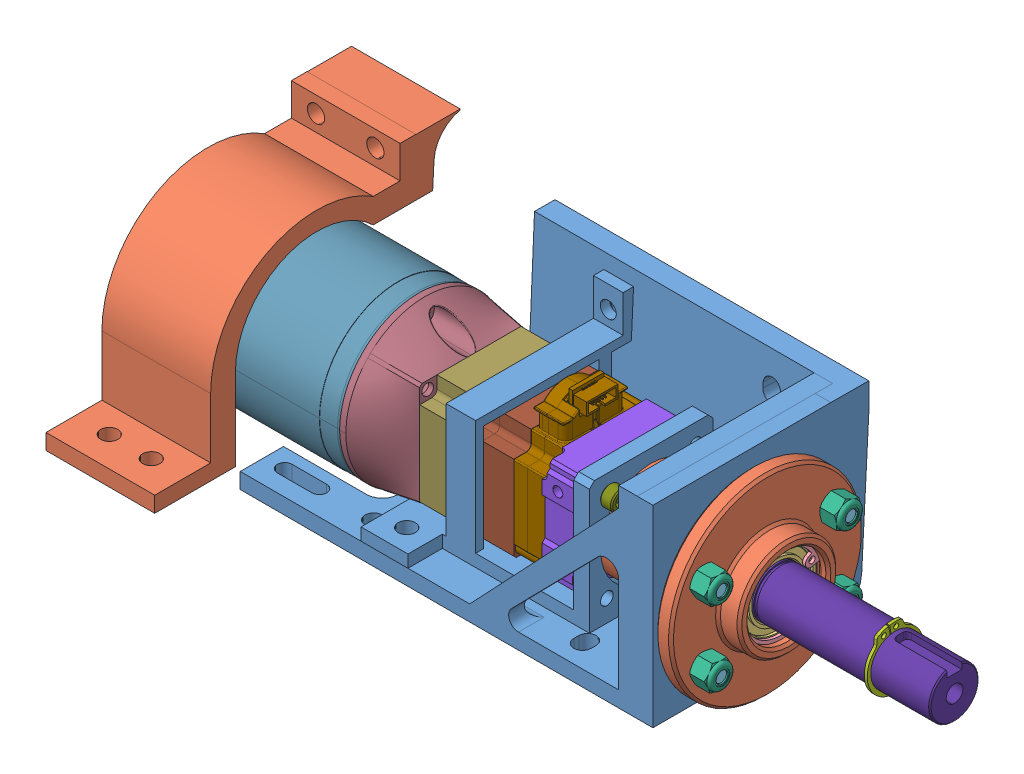
SolidWorks assembly assemblage moteur et sol - V2, configuration Default. Lengths in mm.
Overall size (344.65 86 163.91).
36 component instances, 20 part files, 9 mates.
Components (placement in the parent):
- braquette_bleue_46.2_SLDPRT-1: braquette_bleue_46.2_SLDPRT [Default] at (145.2849 88.8778 231.2871) x (-1 0 0) z (0 0 -1) size (205.75 78 138.28)
- A12220103_FRONT_BRACKET_ASSEMBLY-1: A12220103_FRONT_BRACKET_ASSEMBLY [Default] at (109.7849 121.8778 191.2871) x (0 1 0) z (1 0 0) size (78 78 534.65)
  - A12220101_FRONT_CASE_ASSEMBLY-1: A12220101_FRONT_CASE_ASSEMBLY [Default] at origin size (78 78 141.2)
    - 12220103_FRONT_HOUSING-1: 12220103_FRONT_HOUSING [Default] at (-52 141.0744 -192.9876) x (0 0 -1) z (1 0 0) size (60 78 78)
    - BALL BEARING-1: BALL BEARING [6656K203] at origin size (32 32 10)
    - BALL BEARING-2: BALL BEARING [6656K203] at (0 0 41) size (32 32 10)
    - Internal Retaining Ring (98455A129)-1: Internal Retaining Ring (98455A129) [98455A129] at (0.0361 0.7992 46) x (0.998982 -0.045107 0) z (0 0 1) size (34.4 33.81 1.2)
  - M6 x 20mm Steel Hex Head Screw (91310A333)-2: M6 x 20mm Steel Hex Head Screw (91310A333) [91310A333] at (-15.125 -26.1973 37.15) x (0 0 1) z (-0.44141 0.897306 0) size (24.4 11.55 10)
  - M6 x 1mm Steel Hex LockNut (90592A016)-1: M6 x 1mm Steel Hex LockNut (90592A016) [97260A101] at (15.125 -26.1973 41.85) x (0.928554 -0.371196 0) z (-0.371196 -0.928554 0) size (10 8.38 11.55)
  - 20MM External Retaining Ring (98541A123)-4: 20MM External Retaining Ring (98541A123) [98541A123] at (0 0 92.94) x (0 0 1) z (-0.186581 0.98244 0) size (1.2 25.1 22.76)
  - A12220110_FRONT_SHAFT_ASSEMBLY-1: A12220110_FRONT_SHAFT_ASSEMBLY [Default] at (1.7896 0 -19.01) x (0 -1 0) z (0 0 1) size (64.01 67.32 307.03)
    - A12220105_MOTOR_BRACKET_ASSEMBLY-1: A12220105_MOTOR_BRACKET_ASSEMBLY [Default] at origin size (64.01 67.32 280.24) (flexible)
      - 12220106-051 MiniCIM Motor Assembly-1: 12220106-051 MiniCIM Motor Assembly [Default] at origin size (64.01 67.32 218.97)
        - Gearbox Assembly-1: Gearbox Assembly [Default] at (34.0244 -12.4567 -92.7758) x (0 0 1) z (-1 0 0) size (123.35 56.32 44.45)
          - Output Housing-2: Output Housing [Default] at (64.8023 -0.856 18.2213) x (1 0 0) z (0 -1 0) size (75.7 44.45 56.32)
            - Housing-1: Housing [Default] at (19.8785 -6.4219 -11.5232) size (18.13 44.45 42)
            - Encoder.step-1: Encoder.step [Default] at (12.6785 15.8031 -11.5232) x (0 0 1) z (-1 0 0) size (56.32 42 21.21)
            - Gearbox_output_shaft-1: Gearbox_output_shaft [Default] at origin size (63.51 17 17)
          - Ring Gears-1: Ring Gears [Default] at (71.9808 10.6671 11.7994) x (1 0 0) z (0 -1 0) size (32.2 42 42)
          - Ring Gear Stage 3-1: Ring Gear Stage 3 [Default] at (59.2808 10.6671 11.7994) x (1 0 0) z (0 -1 0) size (28.65 42 42)
        - CIM Adaptor.step-1: CIM Adaptor.step [Default] at (0 -1.7896 -68.72) x (0 -1 0) z (-1 0 0) size (64.01 21.63 64.01)
        - Mini CIM-1: Mini CIM [Default] at (0 -1.7896 -80.245) x (0 0 -1) z (1 0 0) size (101.22 64.01 64.01)
        - 8-32 X 3IN LG - Black-Oxide Alloy Steel Socket Head Screw (90044A516)-1: 8-32 X 3IN LG - Black-Oxide Alloy Steel Socket Head Screw (90044A516) [90044A516] at (17.5 15.7104 -75.245) x (-0.08536 0.99635 0) z (0 0 -1) size (6.86 6.86 81.33)
        - 8-32 X 3IN LG - Black-Oxide Alloy Steel Socket Head Screw (90044A516)-3: 8-32 X 3IN LG - Black-Oxide Alloy Steel Socket Head Screw (90044A516) [90044A516] at (-17.5 -19.2896 -75.245) x (-0.242255 0.970213 0) z (0 0 -1) size (6.86 6.86 81.33)
      - 10-32 X 0.875IN LG - Black-Oxide Alloy Steel Socket Head Screw (91251A346)-1: 10-32 X 0.875IN LG - Black-Oxide Alloy Steel Socket Head Screw (91251A346) [91251A346] at (-17.9605 16.1709 6.1805) x (0.130335 0.99147 0) z (0 0 1) size (7.94 7.94 27.67)
      - 10-32 X 0.875IN LG - Black-Oxide Alloy Steel Socket Head Screw (91251A346)-2: 10-32 X 0.875IN LG - Black-Oxide Alloy Steel Socket Head Screw (91251A346) [91251A346] at (17.9605 -19.7501 6.1805) x (0.872398 0.488796 0) z (0 0 1) size (7.94 7.94 27.67)
    - PB2023-M005 ROTARY SHAFT-1: PB2023-M005 ROTARY SHAFT [Default] at (0 -1.7896 136.57) x (0 0 -1) z (1 0 0) size (126.56 25 25)
    - 12220110_MOTOR_KEY-1: 12220110_MOTOR_KEY [Default] at (0 5.1764 16.3975) size (3.17 4.76 26.16)
  - M6 x 20mm Steel Hex Head Screw (91310A333)-7: M6 x 20mm Steel Hex Head Screw (91310A333) [91310A333] at (15.125 -26.1973 37.15) x (0 0 1) z (0.78025 0.625468 0) size (24.4 11.55 10)
  - M6 x 20mm Steel Hex Head Screw (91310A333)-9: M6 x 20mm Steel Hex Head Screw (91310A333) [91310A333] at (15.125 26.1973 37.15) x (0 0 1) z (0.877007 0.480477 0) size (24.4 11.55 10)
  - M6 x 20mm Steel Hex Head Screw (91310A333)-11: M6 x 20mm Steel Hex Head Screw (91310A333) [91310A333] at (-15.0958 26.1466 37.15) x (0 0 1) z (0.947118 0.320887 0) size (24.4 11.55 10)
  - M6 x 1mm Steel Hex LockNut (90592A016)-7: M6 x 1mm Steel Hex LockNut (90592A016) [97260A101] at (-15.125 -26.1973 41.85) x (0.975663 -0.219276 0) z (-0.219276 -0.975663 0) size (10 8.38 11.55)
  - M6 x 1mm Steel Hex LockNut (90592A016)-9: M6 x 1mm Steel Hex LockNut (90592A016) [97260A101] at (-15.125 26.1973 41.85) x (0.995642 -0.093258 0) z (-0.093258 -0.995642 0) size (10 8.38 11.55)
  - M6 x 1mm Steel Hex LockNut (90592A016)-11: M6 x 1mm Steel Hex LockNut (90592A016) [97260A101] at (15.2049 26.151 41.85) x (1 -0.000046 0) z (-0.000046 -1 0) size (10 8.38 11.55)
- braquette gearbox_46.2-1: braquette gearbox_46.2 [Default] at (105.6549 100.2278 217.3481) x (-1 0 0) z (0 -1 0) size (78.5 77.86 66.5)
- braquette moteur- v2-1: braquette moteur- v2 [Default] at (-74.6861 121.8778 191.2837) x (0 0 1) z (-1 0 0) size (123.62 80 44)
Mates (geometry in assembly coordinates):
- Coincident1: coincident anti-aligned: plane of braquette_bleue_46.2_SLDPRT-1 through (145.2849 88.8778 151.2871) normal (1 0 0); plane of A12220103_FRONT_BRACKET_ASSEMBLY-1/A12220101_FRONT_CASE_ASSEMBLY-1/12220103_FRONT_HOUSING-1 through (145.2849 121.8778 191.2871) normal (-1 0 0)
- Concentric1: concentric aligned: circle of braquette_bleue_46.2_SLDPRT-1; circle of A12220103_FRONT_BRACKET_ASSEMBLY-1/A12220101_FRONT_CASE_ASSEMBLY-1/12220103_FRONT_HOUSING-1
- Coincident2: coincident anti-aligned: plane of braquette_bleue_46.2_SLDPRT-1 through (-21.7151 95.2278 151.2871) normal (0 1 0); plane of braquette gearbox_46.2-1 through (105.6549 95.2278 217.3481) normal (0 -1 0)
- Coincident5: coincident aligned: plane of braquette_bleue_46.2_SLDPRT-1 through (145.2849 88.8778 231.2871) normal (0 0 1); plane of braquette gearbox_46.2-1 through (27.1549 95.2278 231.2871) normal (0 0 1)
- Coincident9: coincident anti-aligned: plane of A12220103_FRONT_BRACKET_ASSEMBLY-1/A12220110_FRONT_SHAFT_ASSEMBLY-1/A12220105_MOTOR_BRACKET_ASSEMBLY-1/12220106-051 MiniCIM Motor Assembly-1/Gearbox Assembly-1/Output Housing-2/Housing-1 through (99.3049 99.6528 213.5121) normal (1 0 0); plane of braquette gearbox_46.2-1 through (99.3049 152.7078 217.3481) normal (-1 0 0)
- Parallel3: parallel anti-aligned: plane of A12220103_FRONT_BRACKET_ASSEMBLY-1/A12220110_FRONT_SHAFT_ASSEMBLY-1/A12220105_MOTOR_BRACKET_ASSEMBLY-1/12220106-051 MiniCIM Motor Assembly-1/Gearbox Assembly-1/Ring Gears-1 through (69.9799 100.8778 212.2871) normal (0 -1 0); plane of braquette gearbox_46.2-1 through (105.6549 100.2278 217.3481) normal (0 1 0)
- Concentric7: concentric aligned: cylinder of A12220103_FRONT_BRACKET_ASSEMBLY-1/A12220110_FRONT_SHAFT_ASSEMBLY-1/A12220105_MOTOR_BRACKET_ASSEMBLY-1/12220106-051 MiniCIM Motor Assembly-1/Mini CIM-1 through (10.5299 121.8778 191.2871) axis (-1 0 0) radius 32.004; cylinder of braquette moteur- v2-1 through (-30.6861 121.8778 191.2871) axis (-1 0 0) radius 33
- Coincident12: coincident aligned: plane of A12220103_FRONT_BRACKET_ASSEMBLY-1/A12220110_FRONT_SHAFT_ASSEMBLY-1/A12220105_MOTOR_BRACKET_ASSEMBLY-1/12220106-051 MiniCIM Motor Assembly-1/Mini CIM-1 through (-74.6861 153.7548 191.2871) normal (-1 0 0); plane of braquette moteur- v2-1 through (-74.6861 119.5082 191.4141) normal (-1 0 0)
- Coincident13: coincident aligned: plane of braquette_bleue_46.2_SLDPRT-1 through (145.2849 88.8778 151.2871) normal (0 -1 0); plane of braquette moteur- v2-1 through (-30.6861 88.8778 224.2871) normal (0 -1 0)
